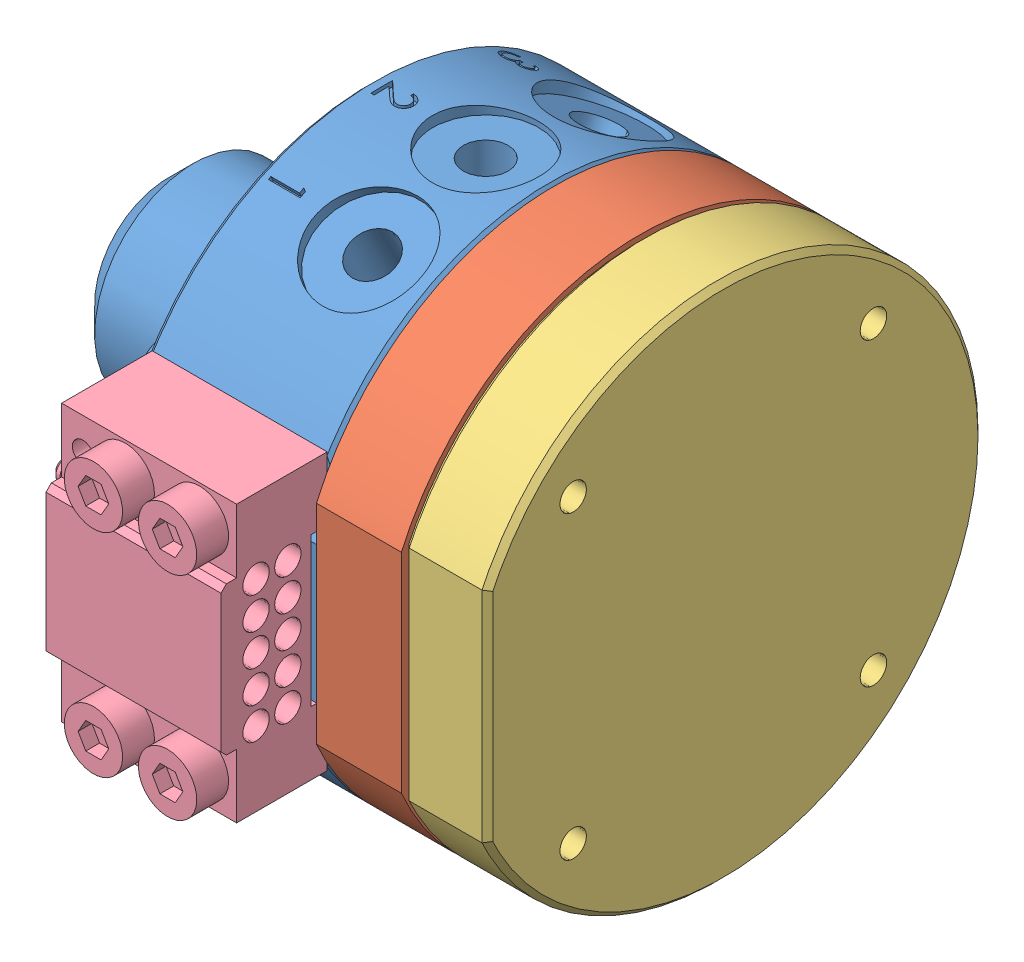
SolidWorks assembly ATI-9120-005M-E10-000-4259, configuration Flat A_E10_Interface Plate_Blank IP_. Lengths in mm.
Overall size (52.37 49.02 56.97).
4 component instances, 4 part files, 9 mates.
Components (placement in the parent):
- ATI-9120-005M-E10-000-4259_QC5-M-1: ATI-9120-005M-E10-000-4259_QC5-M [Default] at origin size (49.07 49 46.95)
- ATI-9120-005M-E10-000-4259_1220-1: ATI-9120-005M-E10-000-4259_1220 [Default] at (3.0226 0 -22.4536) x (0 -1 0) z (-1 0 0) size (49.02 46.96 8)
- ATI-9120-005M-E10-000-4259_4259-1: ATI-9120-005M-E10-000-4259_4259 [Default] at (10.8966 0 -22.4536) x (0 1 0) z (0 0 1) size (49 7.87 46.73)
- ATI-9120-005M-E10-000-4259_E10M-005-1: ATI-9120-005M-E10-000-4259_E10M-005 [Default] at (-21.971 -13.0048 3.4798) x (-1 0 0) z (0 -1 0) size (18.26 17 26.01)
Mates (geometry in assembly coordinates):
- Concentric2: concentric aligned: cylinder of ATI-9120-005M-E10-000-4259_QC5-M-1 through (4.3037 0 -22.4536) axis (1 0 0) radius 16.4935; cylinder of ATI-9120-005M-E10-000-4259_1220-1 through (-4.9784 0 -22.4536) axis (1 0 0) radius 24.511
- Concentric3: concentric aligned: cylinder of ATI-9120-005M-E10-000-4259_QC5-M-1 through (-25.6946 0 -2.4536) axis (-1 0 0) radius 1.5; cylinder of ATI-9120-005M-E10-000-4259_1220-1 through (-4.9784 0 -2.4536) axis (-1 0 0) radius 1.524
- Coincident2: coincident anti-aligned: plane of ATI-9120-005M-E10-000-4259_QC5-M-1 through (-4.9784 0 -46.9519) normal (1 0 0); plane of ATI-9120-005M-E10-000-4259_1220-1 through (-4.9784 0 -22.4536) normal (-1 0 0)
- Concentric6: concentric anti-aligned: cylinder of ATI-9120-005M-E10-000-4259_1220-1 through (-4.9784 0 -22.4536) axis (1 0 0) radius 24.511; cylinder of ATI-9120-005M-E10-000-4259_4259-1 through (10.8966 0 -22.4536) axis (-1 0 0) radius 24.5
- Parallel2: parallel aligned: plane of ATI-9120-005M-E10-000-4259_1220-1 through (-4.9784 9.8298 0) normal (0 0 1); plane of ATI-9120-005M-E10-000-4259_4259-1 through (10.8966 10.3102 -0.2286) normal (0 0 1)
- Coincident5: coincident anti-aligned: plane of ATI-9120-005M-E10-000-4259_1220-1 through (3.0226 0 -22.4536) normal (1 0 0); plane of ATI-9120-005M-E10-000-4259_4259-1 through (3.0226 0 -22.4536) normal (-1 0 0)
- Concentric17: concentric aligned: cylinder of ATI-9120-005M-E10-000-4259_QC5-M-1 through (-15.9766 -9.9949 -1.4986) axis (0 0 1) radius 1.245; cylinder of ATI-9120-005M-E10-000-4259_E10M-005-1 through (-15.9766 -9.9949 -42.9896) axis (0 0 1) radius 1.5
- Parallel10: parallel anti-aligned: plane of ATI-9120-005M-E10-000-4259_QC5-M-1 through (-41.4782 6.9723 0) normal (0 1 0); plane of ATI-9120-005M-E10-000-4259_E10M-005-1 through (-12.9794 7.0104 0) normal (0 -1 0)
- Coincident13: coincident anti-aligned: plane of ATI-9120-005M-E10-000-4259_QC5-M-1 through (-41.4782 6.9723 0) normal (0 0 1); plane of ATI-9120-005M-E10-000-4259_E10M-005-1 through (-12.9794 7.0104 0) normal (0 0 -1)
